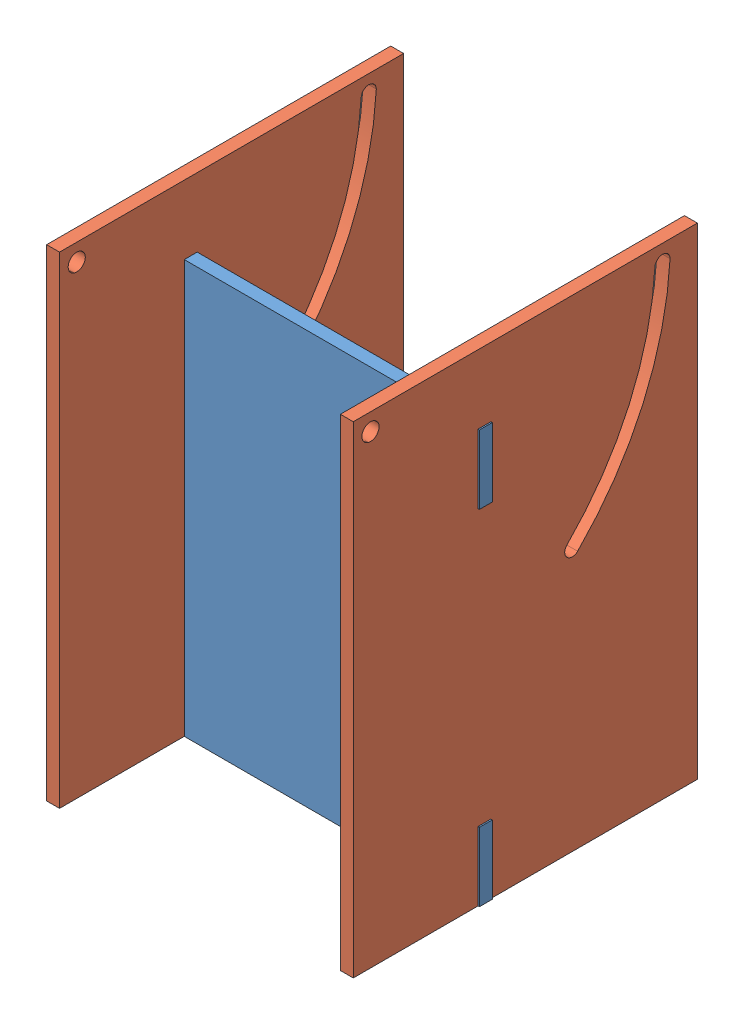
SolidWorks assembly Stand SubAssembly, configuration Default. Lengths in mm.
Overall size (113.69 177.8 127).
3 component instances, 2 part files, 4 mates.
Components (placement in the parent):
- Base Crossbar-1: Base Crossbar [Default] at (-63.5543 -152.4 -7.9169) size (113.67 152.4 4.76)
- Stand Side-1: Stand Side [Default] at (-58.8145 -196.4046 -84.1169) x (0 0 1) z (-1 0 0) size (127 177.8 4.76)
- Stand Side-2: Stand Side [Default] at (49.5985 -196.4046 -84.1169) x (0 0 1) z (-1 0 0) size (127 177.8 4.76)
Mates (geometry in assembly coordinates):
- Coincident1: coincident anti-aligned: plane of Base Crossbar-1 through (-58.7918 -69.4046 -3.1544) normal (0 -1 0); plane of Stand Side-1 through (-63.577 -69.4046 -7.9169) normal (0 1 0)
- Coincident2: coincident anti-aligned: plane of Base Crossbar-1 through (-63.5543 -152.4 -3.1544) normal (0 0 1); plane of Stand Side-1 through (-63.577 -44.0046 -3.1544) normal (0 0 -1)
- Coincident3: coincident anti-aligned: plane of Base Crossbar-1 through (45.3482 -69.4046 -3.1544) normal (0 -1 0); plane of Stand Side-2 through (44.836 -69.4046 -7.9169) normal (0 1 0)
- Coincident4: coincident anti-aligned: plane of Base Crossbar-1 through (-63.5543 -152.4 -7.9169) normal (0 0 -1); plane of Stand Side-2 through (44.836 -44.0046 -7.9169) normal (0 0 1)
